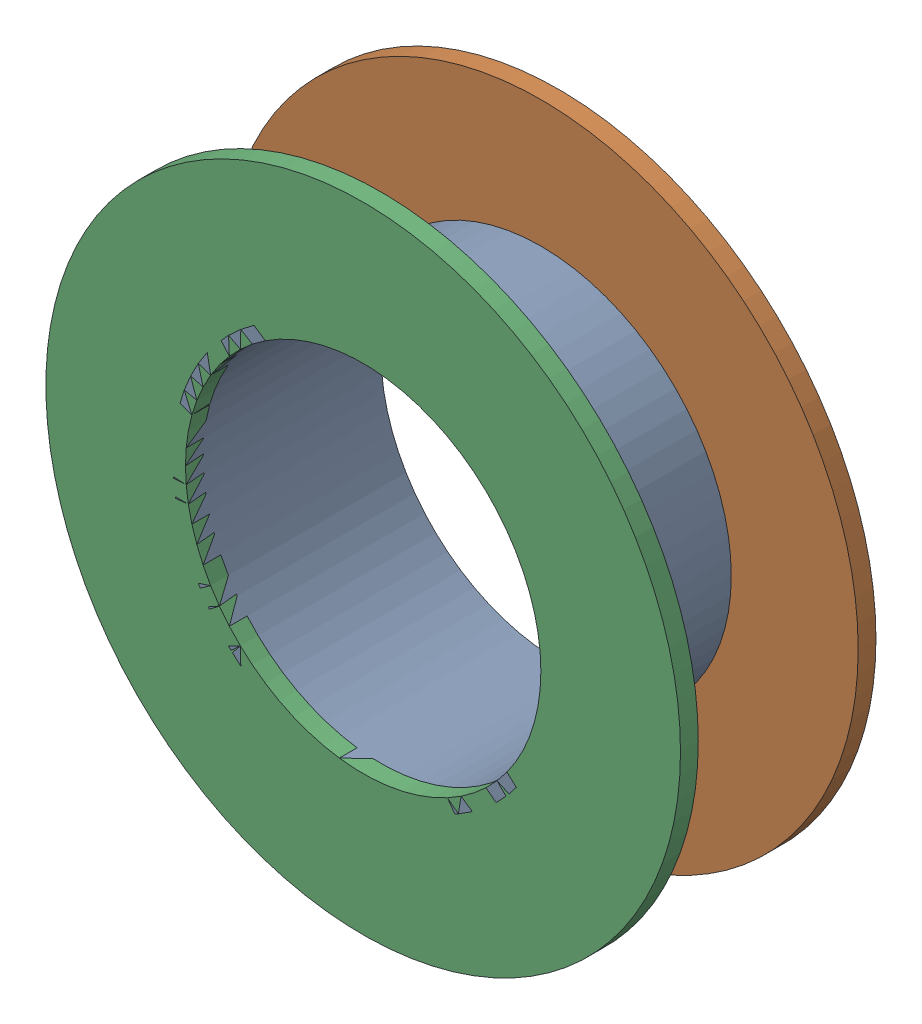
SolidWorks assembly Via (27.75mm,38.55mm) from Top Layer to Bottom Layer, configuration Predeterminado. Lengths in mm.
Overall size (1.27 1.27 0.39).
6 component instances, 2 part files, 0 mates.
Components (placement in the parent):
- Via Hole-1: Via Hole [Predeterminado] at (27.75 38.55 -0.4013) size (0.76 0.76 0.39)
  - Via Hole-Part-1-1: Via Hole-Part-1 [Predeterminado] at origin size (0.76 0.76 0.39)
- Via Top Layer-1: Via Top Layer [Predeterminado] at (27.75 38.55 -0.4013) size (1.27 1.27 0.04)
  - Via Top Layer-Part-1-1: Via Top Layer-Part-1 [Predeterminado] at origin size (1.27 1.27 0.04)
- Via Top Layer-2: Via Top Layer [Predeterminado] at (27.75 38.55 -0.0457) size (1.27 1.27 0.04)
  - Via Top Layer-Part-1-1: Via Top Layer-Part-1 [Predeterminado] at origin size (1.27 1.27 0.04)
